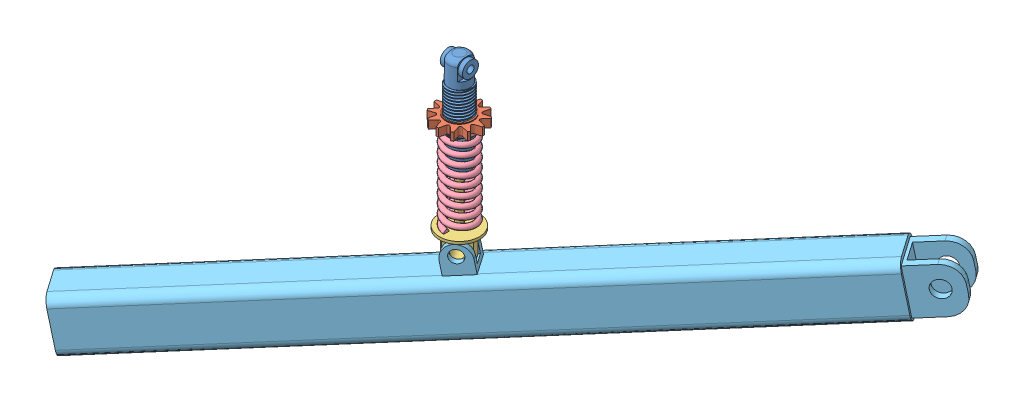
SolidWorks assembly Assem1, configuration Default. Lengths in mm.
Overall size (64.74 32.37 47.24).
5 component instances, 5 part files, 6 mates.
Components (placement in the parent):
- Part3-1: Part3 [Default] at (3.9954 0.4027 8.3329) size (3.12 10.94 2.77)
- Part4-1: Part4 [Default] at (3.9952 4.4965 8.333) x (0.677109 0 -0.735883) z (0.735883 0 0.677109) size (5.08 1.21 5.08)
- Part2-1: Part2 [Default] at (3.994 -5.7782 8.3313) x (-0.571887 0 -0.820332) z (0.820332 0 -0.571887) size (4.5 11.04 4.5)
- Spring-1: Spring [Default] at (4.0017 -5.4819 8.2898) size (3.61 11.19 3.71)
- Part1-2: Part1 [Default] at (4.0533 -12.092 5.0126) x (0.808246 0.171029 -0.563461) z (0.571887 0 0.820332) size (75 9 5)
Mates (geometry in assembly coordinates):
- Screw1: screw = 6 mm anti-aligned: line of Part3-1 through (3.9952 8.4957 8.333) axis (0 -1 0); circle of Part4-1
- Concentric2: concentric aligned: cylinder of Part3-1 through (3.9952 7.4027 8.333) axis (0 -1 0) radius 0.5; cylinder of Part2-1 through (3.9952 1.677 8.333) axis (0 -1 0) radius 0.45
- Coincident2: coincident anti-aligned: plane of Part4-1 through (3.9952 4.4965 8.333) normal (0 -1 0); plane of Spring-1 through (4.0048 4.4965 8.2864) normal (0 1 0)
- Coincident4: coincident anti-aligned: plane of Part2-1 through (3.994 -5.4782 8.3313) normal (0 1 0); plane of Spring-1 through (4.0048 -5.4782 8.2864) normal (0 -1 0)
- Concentric4: concentric anti-aligned: circle of Part2-1; circle of Part1-2
- Coincident9: coincident anti-aligned: plane of Part2-1 through (2.584 -6.1701 10.2431) normal (0.571887 0 0.820332); plane of Part1-2 through (15.2178 -6.4739 1.4355) normal (-0.571887 0 -0.820332)
